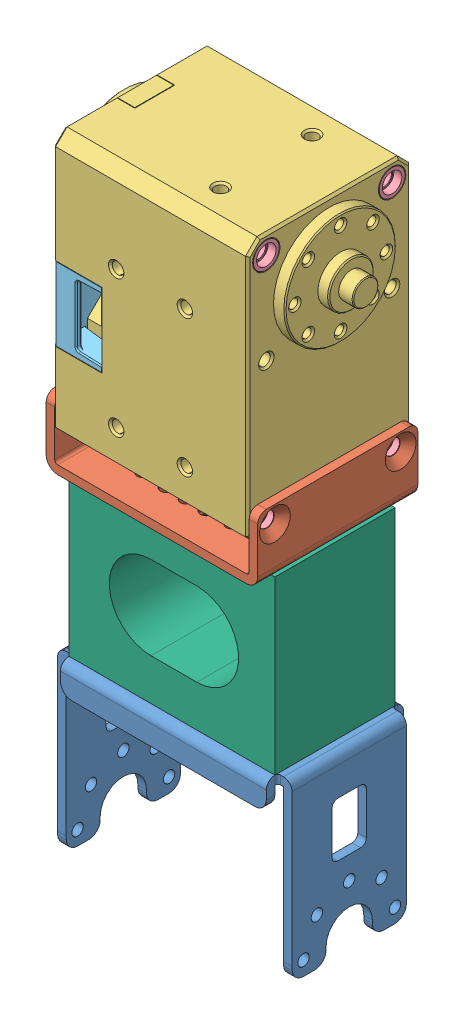
SolidWorks assembly link4_2, configuration 기본. Lengths in mm.
Overall size (43.9 112.25 28.5).
14 component instances, 6 part files, 9 mates.
Components (placement in the parent):
- fr12_h101-1: fr12_h101 [기본] at (-2.5744 -12.4757 41) size (41 30.5 24)
- fr12_s102-1: fr12_s102 [기본] at (-2.5744 65.0243 41) x (1 0 0) z (0 -1 0) size (37 28 11.5)
- x-430_idle-1: x-430_idle [기본] at (-2.5744 86.0243 41) x (0 0 -1) z (1 0 0) size (28.5 46.5 42.4)
  - X-430_IDLE-1: X-430_IDLE [기본] at origin size (28.5 46.5 42.4)
  - X-430_SPACER_RING-1: X-430_SPACER_RING [기본] at (11 8 14.2) x (-1 0 0) z (0 1 0) size (4.8 2.8 4.8)
  - X-430_SPACER_RING-2: X-430_SPACER_RING [기본] at (-11 8 14.2) x (-1 0 0) z (0 1 0) size (4.8 2.8 4.8)
  - X-430_SPACER_RING-3: X-430_SPACER_RING [기본] at (11 -32 14.2) x (-1 0 0) z (0 1 0) size (4.8 2.8 4.8)
  - X-430_SPACER_RING-4: X-430_SPACER_RING [기본] at (-11 -32 14.2) x (-1 0 0) z (0 1 0) size (4.8 2.8 4.8)
  - X-430_SPACER_RING-5: X-430_SPACER_RING [기본] at (-11 8 -14.2) x (1 0 0) z (0 1 0) size (4.8 2.8 4.8)
  - X-430_SPACER_RING-6: X-430_SPACER_RING [기본] at (11 8 -14.2) x (1 0 0) z (0 1 0) size (4.8 2.8 4.8)
  - X-430_SPACER_RING-7: X-430_SPACER_RING [기본] at (-11 -32 -14.2) x (1 0 0) z (0 1 0) size (4.8 2.8 4.8)
  - X-430_SPACER_RING-8: X-430_SPACER_RING [기본] at (11 -32 -14.2) x (1 0 0) z (0 1 0) size (4.8 2.8 4.8)
  - X-430_CVR_CABLE-1: X-430_CVR_CABLE [기본] at origin size (28.5 12.8 8.8)
- linkframe2_1-1: linkframe2_1 [기본] at (-2.5744 45.5243 41) x (1 0 0) z (0 -1 0) size (36 21 30)
Mates (geometry in assembly coordinates):
- 동심5: concentric anti-aligned: circle of fr12_s102-1; circle of x-430_idle-1/X-430_SPACER_RING-4
- 동심6: concentric anti-aligned: circle of fr12_s102-1; circle of x-430_idle-1/X-430_SPACER_RING-3
- 너비1: width aligned: plane of fr12_s102-1 through (-19.5744 47.5243 27) normal (1 0 0); plane of fr12_s102-1 through (14.4256 57.0243 27) normal (-1 0 0); plane of x-430_idle-1/X-430_IDLE-1 through (14.4256 86.0243 41) normal (1 0 0); plane of x-430_idle-1/X-430_IDLE-1 through (-19.5744 86.0243 41) normal (-1 0 0)
- Concentric1: concentric aligned: circle of fr12_h101-1; circle of linkframe2_1-1
- Concentric2: concentric aligned: circle of fr12_h101-1; circle of linkframe2_1-1
- Coincident1: coincident anti-aligned: plane of fr12_h101-1 through (-21.5744 15.5243 51) normal (0 1 0); plane of linkframe2_1-1 through (-2.5744 15.5243 41) normal (0 -1 0)
- Concentric3: concentric aligned: circle of fr12_s102-1; circle of linkframe2_1-1
- Concentric4: concentric anti-aligned: circle of fr12_s102-1; circle of linkframe2_1-1
- Coincident2: coincident anti-aligned: plane of fr12_s102-1 through (13.9256 45.5243 27) normal (0 -1 0); plane of linkframe2_1-1 through (-2.5744 45.5243 41) normal (0 1 0)
